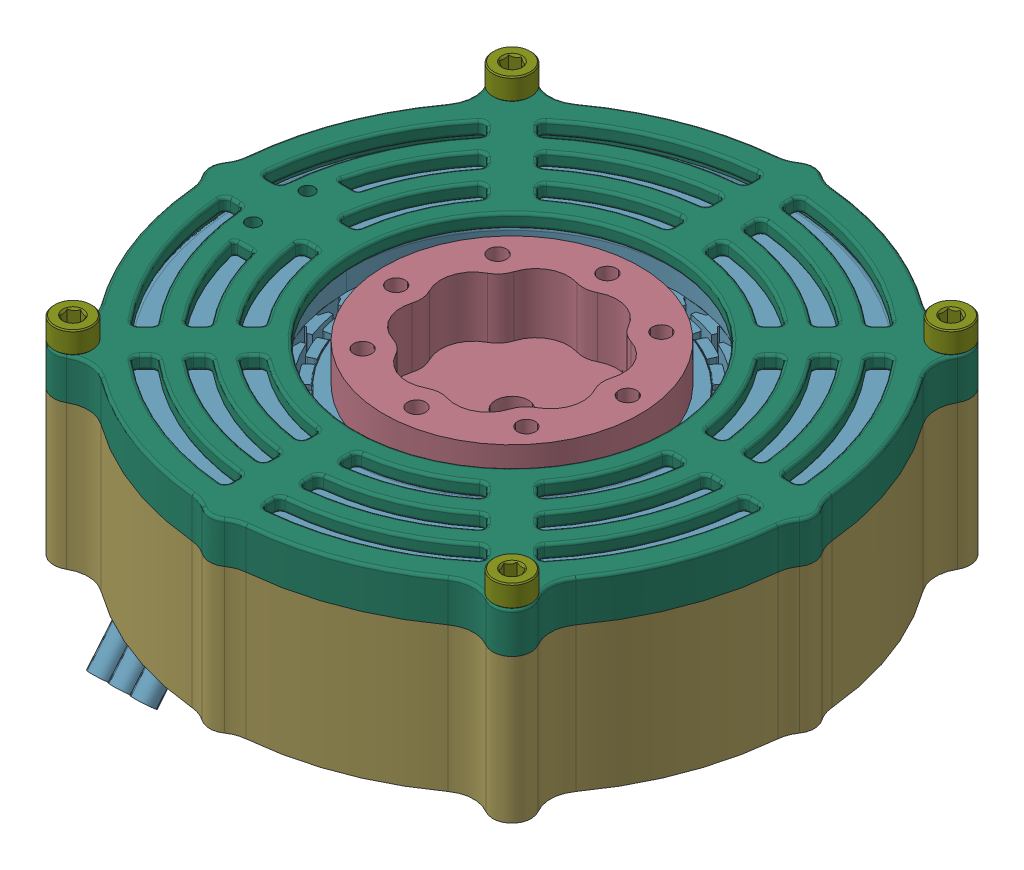
SolidWorks assembly MainMotorASM, configuration Default. Lengths in mm.
Overall size (111 65.11 111).
37 component instances, 17 part files, 41 mates.
Components (placement in the parent):
- 60355K45_Ball Bearing-1: 60355K45_Ball Bearing [60355K45] at (0 -28.6962 0) x (-0.264563 0 0.964368) z (0 1 0) size (22.23 22.23 7.14)
- 60355K45_Ball Bearing-2: 60355K45_Ball Bearing [60355K45] at (0 -17.0689 0) x (0.972467 0 0.233041) z (0 1 0) size (22.23 22.23 7.14)
- 97633A170_External Retaining Ring-1: 97633A170_External Retaining Ring [97633A170] at (0 -32.5779 0) x (0 -1 0) z (-0.728476 0 0.685072) size (0.64 12.09 10.6)
- 97049A330_Undersized Dowel Pin-1: 97049A330_Undersized Dowel Pin [97049A330] at (52 -17.5009 0.0179) x (0 1 0) z (-0.846181 0 0.532895) size (20 3 3)
- 97049A330_Undersized Dowel Pin-2: 97049A330_Undersized Dowel Pin [97049A330] at (-0.0179 -17.5009 52) x (0 1 0) z (0 0 1) size (20 3 3)
- 97049A330_Undersized Dowel Pin-3: 97049A330_Undersized Dowel Pin [97049A330] at (-52 -17.5009 -0.0179) x (0 1 0) z (0 0 1) size (20 3 3)
- 97049A330_Undersized Dowel Pin-4: 97049A330_Undersized Dowel Pin [97049A330] at (0.0179 -17.5009 -52) x (0 1 0) z (0 0 1) size (20 3 3)
- 91290A100_Black-Oxide Alloy Steel Socket Head Screw-1: 91290A100_Black-Oxide Alloy Steel Socket Head Screw [91290A100] at (-23.0125 -35.2508 0) x (-0.909726 0 -0.41521) z (0 -1 0) size (4.5 4.5 7.62)
- 91290A100_Black-Oxide Alloy Steel Socket Head Screw-2: 91290A100_Black-Oxide Alloy Steel Socket Head Screw [91290A100] at (23.0125 -35.2508 0) x (0.699235 0 -0.714892) z (0 -1 0) size (4.5 4.5 7.62)
- ATM102 Encoder-1: ATM102 Encoder [Default] at (0 -36.5008 0) x (1 0 0) z (0 -1 0) size (52.5 43.39 9.13)
  - ATM102 Encoder(2)^ATM102 Encoder-1: ATM102 Encoder(2)^ATM102 Encoder [Default] at origin size (52.5 43.39 9.13) (virtual)
    - Array002^ATM102 Encoder(2)_ATM102 Encoder-1: Array002^ATM102 Encoder(2)_ATM102 Encoder [Default] at (5.1 -17.2 2.6) x (-1 0 0) z (0 0 -1) size (10.79 9.97 4.13) (virtual)
      - Body007^Array002_ATM102 Encoder(2)_ATM102 Encoder-1: Body007^Array002_ATM102 Encoder(2)_ATM102 Encoder [Default] at (0 0 -2.54) size (0.64 9.97 4.13) (virtual)
      - Body007^Array002_ATM102 Encoder(2)_ATM102 Encoder-2: Body007^Array002_ATM102 Encoder(2)_ATM102 Encoder [Default] at (2.54 0 -2.54) size (0.64 9.97 4.13) (virtual)
      - Body007^Array002_ATM102 Encoder(2)_ATM102 Encoder-3: Body007^Array002_ATM102 Encoder(2)_ATM102 Encoder [Default] at (5.08 0 -2.54) size (0.64 9.97 4.13) (virtual)
      - Body007^Array002_ATM102 Encoder(2)_ATM102 Encoder-4: Body007^Array002_ATM102 Encoder(2)_ATM102 Encoder [Default] at (7.62 0 -2.54) size (0.64 9.97 4.13) (virtual)
      - Body007^Array002_ATM102 Encoder(2)_ATM102 Encoder-5: Body007^Array002_ATM102 Encoder(2)_ATM102 Encoder [Default] at (10.16 0 -2.54) size (0.64 9.97 4.13) (virtual)
    - Array003^ATM102 Encoder(2)_ATM102 Encoder-1: Array003^ATM102 Encoder(2)_ATM102 Encoder [Default] at (5.1 -16.7 2.6) x (-1 0 0) z (0 0 -1) size (12.7 3 2.54) (virtual)
      - Body008^Array003_ATM102 Encoder(2)_ATM102 Encoder-1: Body008^Array003_ATM102 Encoder(2)_ATM102 Encoder [Default] at (0 -1.27 1.27) x (1 0 0) z (0 -1 0) size (2.54 2.54 3) (virtual)
      - Body008^Array003_ATM102 Encoder(2)_ATM102 Encoder-2: Body008^Array003_ATM102 Encoder(2)_ATM102 Encoder [Default] at (2.54 -1.27 1.27) x (1 0 0) z (0 -1 0) size (2.54 2.54 3) (virtual)
      - Body008^Array003_ATM102 Encoder(2)_ATM102 Encoder-3: Body008^Array003_ATM102 Encoder(2)_ATM102 Encoder [Default] at (5.08 -1.27 1.27) x (1 0 0) z (0 -1 0) size (2.54 2.54 3) (virtual)
      - Body008^Array003_ATM102 Encoder(2)_ATM102 Encoder-4: Body008^Array003_ATM102 Encoder(2)_ATM102 Encoder [Default] at (7.62 -1.27 1.27) x (1 0 0) z (0 -1 0) size (2.54 2.54 3) (virtual)
      - Body008^Array003_ATM102 Encoder(2)_ATM102 Encoder-5: Body008^Array003_ATM102 Encoder(2)_ATM102 Encoder [Default] at (10.16 -1.27 1.27) x (1 0 0) z (0 -1 0) size (2.54 2.54 3) (virtual)
    - Body^ATM102 Encoder(2)_ATM102 Encoder-1: Body^ATM102 Encoder(2)_ATM102 Encoder [Default] at origin size (28.77 42.85 6.5) (virtual)
    - Body001^ATM102 Encoder(2)_ATM102 Encoder-1: Body001^ATM102 Encoder(2)_ATM102 Encoder [Default] at origin size (52.5 43.39 9.03) (virtual)
    - Chamfer002^ATM102 Encoder(2)_ATM102 Encoder-1: Chamfer002^ATM102 Encoder(2)_ATM102 Encoder [Default] at origin size (14 14 9.13) (virtual)
    - Chamfer004^ATM102 Encoder(2)_ATM102 Encoder-1: Chamfer004^ATM102 Encoder(2)_ATM102 Encoder [Default] at (0 0 0.5) size (12.2 12.2 9) (virtual)
    - Body006^ATM102 Encoder(2)_ATM102 Encoder-1: Body006^ATM102 Encoder(2)_ATM102 Encoder [Default] at (0 0 -2.5) size (9 9 9) (virtual)
- Stator-1: Stator [Default] at origin size (111 26.5 111)
- Rotor-1: Rotor [Default] at (0 0.0038 0) x (0.469589 0 0.882885) z (-0.882885 0 0.469589) size (47 43 47)
- RI100-210120-1: RI100-210120 [Default] at (0 -14.0006 0) x (-1 0 -0.000344) z (0 -1 0) size (103.96 103.96 58.03)
- Part1^MainMotorASM-1: Part1^MainMotorASM [Default] at origin (suppressed, hidden, virtual)
- Part2^MainMotorASM-1: Part2^MainMotorASM [Default] at (0 -7.5009 0) x (1 0 0) z (0 1 0) size (111 111 7.54) (virtual)
- 91290A144_Alloy Steel Socket Head Screw-5: 91290A144_Alloy Steel Socket Head Screw [91290A144] at (40.3051 -2.9609 40.3051) x (-0.797298 0 -0.603586) z (0 1 0) size (7 7 14.04)
- 91290A144_Alloy Steel Socket Head Screw-6: 91290A144_Alloy Steel Socket Head Screw [91290A144] at (40.3051 -2.9609 -40.3051) x (1 0 0) z (0 1 0) size (7 7 14.04)
- 91290A144_Alloy Steel Socket Head Screw-7: 91290A144_Alloy Steel Socket Head Screw [91290A144] at (-40.3051 -2.9609 -40.3051) x (1 0 0) z (0 1 0) size (7 7 14.04)
- 91290A144_Alloy Steel Socket Head Screw-4: 91290A144_Alloy Steel Socket Head Screw [91290A144] at (-40.3051 -2.9609 40.3051) x (0.332759 0 -0.943012) z (0 1 0) size (7 7 14.04)
Mates (geometry in assembly coordinates):
- Coincident5: coincident anti-aligned: plane of ATM102 Encoder-1/ATM102 Encoder(2)^ATM102 Encoder-1/Body001^ATM102 Encoder(2)_ATM102 Encoder-1 through (0 -34.0008 -6.0589) normal (0 1 0); plane of Stator-1 through (0 -34.0008 0) normal (0 -1 0)
- Coincident6: coincident anti-aligned: plane of Stator-1 through (0 -20.5006 0) normal (0 1 0); plane of RI100-210120-1 through (0 -20.5006 0) normal (0 -1 0)
- Concentric7: concentric aligned: cylinder of Stator-1 through (0 -34.0008 0) axis (0 -1 0) radius 52; cylinder of RI100-210120-1 through (0 -14.0006 0) axis (0 -1 0) radius 52
- Distance1: distance = 0.0179 mm: cylinder of RI100-210120-1 through (52 -14.0006 0.0179) axis (0 -1 0) radius 1.5; cylinder of Stator-1 through (52 -7.5009 0) axis (0 1 0) radius 1.5
- Concentric8: concentric anti-aligned: cylinder of RI100-210120-1 through (-0.0179 -14.0006 52) axis (0 -1 0) radius 1.5; cylinder of 97049A330_Undersized Dowel Pin-2 through (-0.0179 -27.5009 52) axis (0 1 0) radius 1.5
- Concentric9: concentric anti-aligned: cylinder of RI100-210120-1 through (52 -14.0006 0.0179) axis (0 -1 0) radius 1.5; cylinder of 97049A330_Undersized Dowel Pin-1 through (52 -27.5009 0.0179) axis (0 1 0) radius 1.5
- Concentric10: concentric anti-aligned: cylinder of RI100-210120-1 through (-52 -14.0006 -0.0179) axis (0 -1 0) radius 1.5; cylinder of 97049A330_Undersized Dowel Pin-3 through (-52 -27.5009 -0.0179) axis (0 1 0) radius 1.5
- Concentric11: concentric anti-aligned: cylinder of RI100-210120-1 through (0.0179 -14.0006 -52) axis (0 -1 0) radius 1.5; cylinder of 97049A330_Undersized Dowel Pin-4 through (0.0179 -27.5009 -52) axis (0 1 0) radius 1.5
- Coincident7: coincident aligned: plane of 97049A330_Undersized Dowel Pin-3 through (-52 -7.5009 -0.0179) normal (0 1 0); plane of 97049A330_Undersized Dowel Pin-4 through (0.0179 -7.5009 -52) normal (0 1 0)
- Coincident8: coincident aligned: plane of 97049A330_Undersized Dowel Pin-2 through (-0.0179 -7.5009 52) normal (0 1 0); plane of 97049A330_Undersized Dowel Pin-3 through (-52 -7.5009 -0.0179) normal (0 1 0)
- Coincident9: coincident aligned: plane of 97049A330_Undersized Dowel Pin-1 through (52 -7.5009 0.0179) normal (0 1 0); plane of 97049A330_Undersized Dowel Pin-2 through (-0.0179 -7.5009 52) normal (0 1 0)
- Coincident10: coincident anti-aligned: circle of Stator-1; plane of 97049A330_Undersized Dowel Pin-1 through (52 -27.5009 0.0179) normal (0 -1 0)
- Concentric12: concentric aligned: cylinder of ATM102 Encoder-1/ATM102 Encoder(2)^ATM102 Encoder-1/Body006^ATM102 Encoder(2)_ATM102 Encoder-1 through (0 -34.0008 0) axis (0 -1 0) radius 3.175; cylinder of Rotor-1 through (0 -33.997 0) axis (0 -1 0) radius 3.175
- Concentric13: concentric anti-aligned: cylinder of ATM102 Encoder-1/ATM102 Encoder(2)^ATM102 Encoder-1/Body001^ATM102 Encoder(2)_ATM102 Encoder-1 through (23.0125 -36.5008 0) axis (0 1 0) radius 1.435; cylinder of Stator-1 through (23.0125 -34.0008 0) axis (0 -1 0) radius 1.025
- Concentric14: concentric aligned: cylinder of 91290A100_Black-Oxide Alloy Steel Socket Head Screw-1 through (-23.0125 -31.5008 0) axis (0 1 0) radius 1.25; cylinder of ATM102 Encoder-1/ATM102 Encoder(2)^ATM102 Encoder-1/Body001^ATM102 Encoder(2)_ATM102 Encoder-1 through (-23.0125 -36.5008 0) axis (0 1 0) radius 1.435
- Concentric15: concentric aligned: cylinder of 91290A100_Black-Oxide Alloy Steel Socket Head Screw-2 through (23.0125 -31.5008 0) axis (0 1 0) radius 1.25; cylinder of ATM102 Encoder-1/ATM102 Encoder(2)^ATM102 Encoder-1/Body001^ATM102 Encoder(2)_ATM102 Encoder-1 through (23.0125 -36.5008 0) axis (0 1 0) radius 1.435
- Coincident11: coincident anti-aligned: plane of 91290A100_Black-Oxide Alloy Steel Socket Head Screw-1 through (-22.1302 -36.5008 -1.9332) normal (0 1 0); plane of ATM102 Encoder-1/ATM102 Encoder(2)^ATM102 Encoder-1/Body001^ATM102 Encoder(2)_ATM102 Encoder-1 through (0 -36.5008 -6.0589) normal (0 -1 0)
- Coincident12: coincident anti-aligned: plane of 91290A100_Black-Oxide Alloy Steel Socket Head Screw-2 through (24.5316 -36.5008 1.4859) normal (0 1 0); plane of ATM102 Encoder-1/ATM102 Encoder(2)^ATM102 Encoder-1/Body001^ATM102 Encoder(2)_ATM102 Encoder-1 through (0 -36.5008 -6.0589) normal (0 -1 0)
- Coincident13: coincident aligned: plane of Stator-1 through (0 0 0) normal (0 0 1)
- Coincident14: coincident aligned: plane of Stator-1 through (0 0 0) normal (0 1 0)
- Coincident15: coincident aligned: plane of Stator-1 through (0 0 0) normal (1 0 0)
- InPlace1: in place: plane of ? through (0 -7.5009 0) normal (0 1 0); plane of Part2^MainMotorASM-1 through (0 -7.5009 0) normal (0 1 0); moOrthogonalPlaneRef_w of ? through (0 -7.5009 0) normal (0 1 0); plane of Part2^MainMotorASM-1 through (0 -7.5009 0) normal (0 0 -1); plane of ? through (0 -7.5009 0) normal (0 1 0); plane of Part2^MainMotorASM-1 through (0 -7.5009 0) normal (1 0 0); plane of ? through (0 -7.5009 0) normal (0 1 0); unknown of Part2^MainMotorASM-1
- Coincident16: coincident aligned: plane of Stator-1; plane of Part2^MainMotorASM-1
- Coincident17: coincident aligned: moOrthogonalPlaneRef_w of Stator-1 through (0 -7.5009 0) normal (0 0 -1); plane of Part2^MainMotorASM-1 through (0 -7.5009 0) normal (0 0 -1)
- Coincident18: coincident anti-aligned: moOrthogonalPlaneRef_w of Stator-1 through (0 -7.5009 0) normal (-1 0 0); plane of Part2^MainMotorASM-1 through (0 -7.5009 0) normal (1 0 0)
- Concentric16: concentric anti-aligned: cylinder of 60355K45_Ball Bearing-1 through (0 -25.1243 0) axis (0 1 0) radius 11.1125; cylinder of Stator-1 through (0 -34.0008 0) axis (0 -1 0) radius 11.1125
- Coincident16: coincident anti-aligned: plane of 60355K45_Ball Bearing-1 through (10.3721 -25.1243 2.8455) normal (0 1 0); plane of Stator-1 through (0 -25.1243 0) normal (0 -1 0)
- Concentric17: concentric aligned: cylinder of Stator-1 through (0 -34.0008 0) axis (0 -1 0) radius 14.5; cylinder of Rotor-1 through (0 -33.997 0) axis (0 -1 0) radius 23.5
- Concentric18: concentric anti-aligned: cylinder of Part2^MainMotorASM-1 through (40.3051 0.0391 40.3051) axis (0 1 0) radius 2.25; cylinder of 91290A144_Alloy Steel Socket Head Screw-5 through (40.3051 -9.9609 40.3051) axis (0 -1 0) radius 2
- Concentric19: concentric anti-aligned: cylinder of Part2^MainMotorASM-1 through (40.3051 0.0391 -40.3051) axis (0 1 0) radius 2.25; cylinder of 91290A144_Alloy Steel Socket Head Screw-6 through (40.3051 -9.9609 -40.3051) axis (0 -1 0) radius 2
- Concentric20: concentric anti-aligned: cylinder of Part2^MainMotorASM-1 through (-40.3051 0.0391 -40.3051) axis (0 1 0) radius 2.25; cylinder of 91290A144_Alloy Steel Socket Head Screw-7 through (-40.3051 -9.9609 -40.3051) axis (0 -1 0) radius 2
- Concentric21: concentric anti-aligned: cylinder of Part2^MainMotorASM-1 through (-40.3051 0.0391 40.3051) axis (0 1 0) radius 2.25; cylinder of 91290A144_Alloy Steel Socket Head Screw-4 through (-40.3051 -9.9609 40.3051) axis (0 -1 0) radius 2
- Coincident17: coincident aligned: plane of 91290A144_Alloy Steel Socket Head Screw-6 through (40.3051 4.0391 -40.3051) normal (0 1 0); plane of 91290A144_Alloy Steel Socket Head Screw-7 through (-40.3051 4.0391 -40.3051) normal (0 1 0)
- Coincident18: coincident aligned: plane of 91290A144_Alloy Steel Socket Head Screw-5 through (40.3051 4.0391 40.3051) normal (0 1 0); plane of 91290A144_Alloy Steel Socket Head Screw-6 through (40.3051 4.0391 -40.3051) normal (0 1 0)
- Coincident19: coincident aligned: plane of 91290A144_Alloy Steel Socket Head Screw-5 through (40.3051 4.0391 40.3051) normal (0 1 0); plane of 91290A144_Alloy Steel Socket Head Screw-4 through (-40.3051 4.0391 40.3051) normal (0 1 0)
- Coincident20: coincident anti-aligned: plane of Part2^MainMotorASM-1 through (-17.7013 0.0391 -24.2212) normal (0 1 0); plane of 91290A144_Alloy Steel Socket Head Screw-4 through (-43.417 0.0391 39.207) normal (0 -1 0)
- Concentric22: concentric anti-aligned: cylinder of 97633A170_External Retaining Ring-1 through (0 -32.8954 0) axis (0 1 0) radius 4.2926; cylinder of Rotor-1 through (0 -33.997 0) axis (0 -1 0) radius 4.4704
- Coincident21: coincident anti-aligned: plane of 97633A170_External Retaining Ring-1 through (-0.1812 -32.2604 -0.1927) normal (0 1 0); plane of Rotor-1 through (0 -32.2604 0) normal (0 -1 0)
- Concentric23: concentric anti-aligned: cylinder of 60355K45_Ball Bearing-2 through (0 -13.4971 0) axis (0 1 0) radius 11.1125; cylinder of Stator-1 through (0 -34.0008 0) axis (0 -1 0) radius 11.1125
- Coincident22: coincident anti-aligned: plane of 60355K45_Ball Bearing-2 through (1.6953 -13.4971 -7.0743) normal (0 1 0); plane of Rotor-1 through (0 -13.4971 0) normal (0 -1 0)
- Coincident23: coincident anti-aligned: plane of 60355K45_Ball Bearing-2 through (2.5064 -20.6408 -10.4592) normal (0 -1 0); plane of Stator-1 through (0 -20.6408 0) normal (0 1 0)
